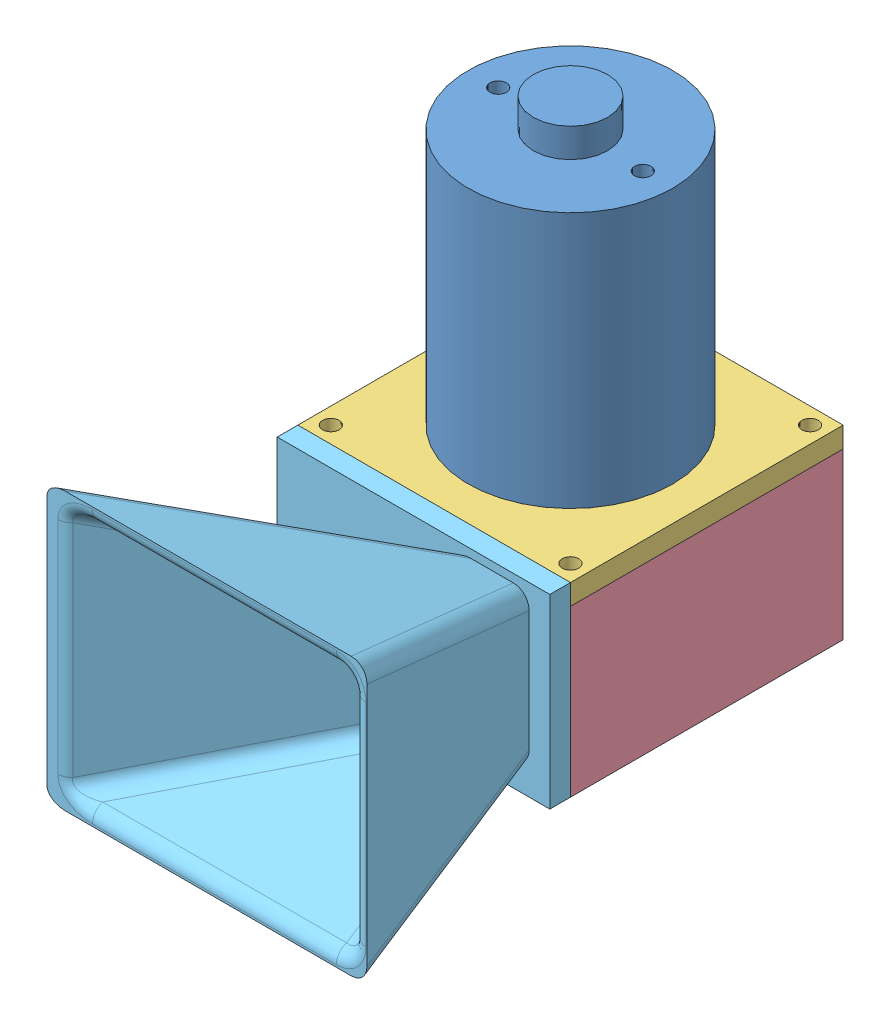
SolidWorks assembly full assembly, configuration Default. Lengths in mm.
Overall size (77.5 123 122.24).
5 component instances, 5 part files, 11 mates.
Components (placement in the parent):
- ato wp500-1: ato wp500 [Default] at (26.8031 0 91.8614) x (1 0 0) z (0 -1 0) size (49.5 49.5 113)
- impeller-1: impeller [Default] at (26.8031 -20.5 91.8614) x (-0.837169 0 -0.546944) z (0 -1 0) size (49.48 49.48 30)
- impeller plate-1: impeller plate [Default] at (26.8031 -2.5 91.8614) x (1 0 0) z (0 -1 0) size (66 66 5)
- impeller housing-1: impeller housing [Default] at (26.8031 -45 91.8614) size (66 40 66)
- duct-1: duct [Default] at (45.5531 -20.5 124.8614) size (77.5 67 55)
Mates (geometry in assembly coordinates):
- Coincident2: coincident: plane of ato wp500-1 through (26.8031 0 91.8614) normal (0 -1 0); plane of assembly through (0 0 0) normal (0 1 0)
- Concentric1: concentric: circle of ato wp500-1; circle of impeller-1
- Distance1: distance = 8.5 mm: plane of impeller-1 through (4.1439 -35.5 100.9475) normal (0 -1 0); plane of ato wp500-1 through (26.8031 -44 91.8614) normal (0 -1 0)
- Coincident6: coincident: plane of ato wp500-1 through (26.8031 0 91.8614) normal (0 -1 0); plane of impeller plate-1 through (26.8031 0 91.8614) normal (0 1 0)
- Concentric2: concentric: circle of ato wp500-1; circle of impeller plate-1
- Concentric3: concentric: circle of ato wp500-1; circle of impeller plate-1
- Coincident10: coincident: plane of impeller plate-1 through (26.8031 -5 91.8614) normal (0 -1 0); plane of impeller housing-1 through (26.8031 -5 91.8614) normal (0 1 0)
- Concentric4: concentric: circle of impeller plate-1; circle of impeller housing-1
- Coincident13: coincident: plane of impeller housing-1 through (-6.1969 -5 124.8614) normal (0 0 1); plane of duct-1 through (45.5531 -20.5 124.8614) normal (0 0 -1)
- Coincident14: coincident: plane of impeller housing-1 through (51.8031 -5 58.8614) normal (-1 0 0); plane of duct-1 through (51.8031 -36 129.8614) normal (-1 0 0)
- Coincident15: coincident: plane of impeller housing-1 through (26.8031 -36 91.8614) normal (0 1 0); plane of duct-1 through (39.3031 -36 129.8614) normal (0 1 0)
